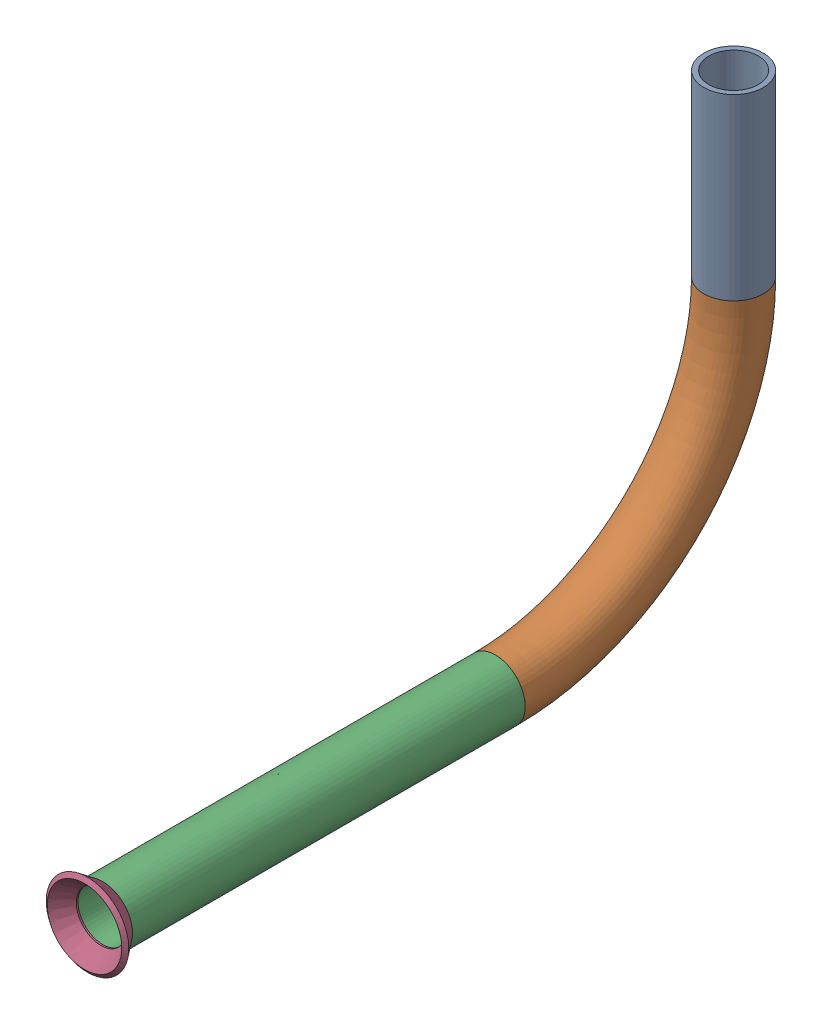
SolidWorks assembly Pipe 35, configuration Default. Lengths in mm.
Overall size (17.59 97.7 144.75).
2 component instances, 2 part files, 2 mates.
Components (placement in the parent):
- Part11-1: Part11 [Default<As Machined>] at origin size (12.7 95.25 140.86)
- Flared pipe end - .5 inch-2: Flared pipe end - .5 inch [Default<As Machined>] at (0 -280.0604 393.6907) x (1 -0.00017 0) z (0 0 1) size (17.59 17.59 3.89)
Mates (geometry in assembly coordinates):
- Coincident1033: coincident: plane of Part11-1 through (0 -280.0604 393.6907) normal (0 0 1); plane of Flared pipe end - .5 inch-2 through (0.0009 -274.7772 393.6907) normal (0 0 -1)
- Concentric659: concentric: circle of Part11-1; circle of Flared pipe end - .5 inch-2
